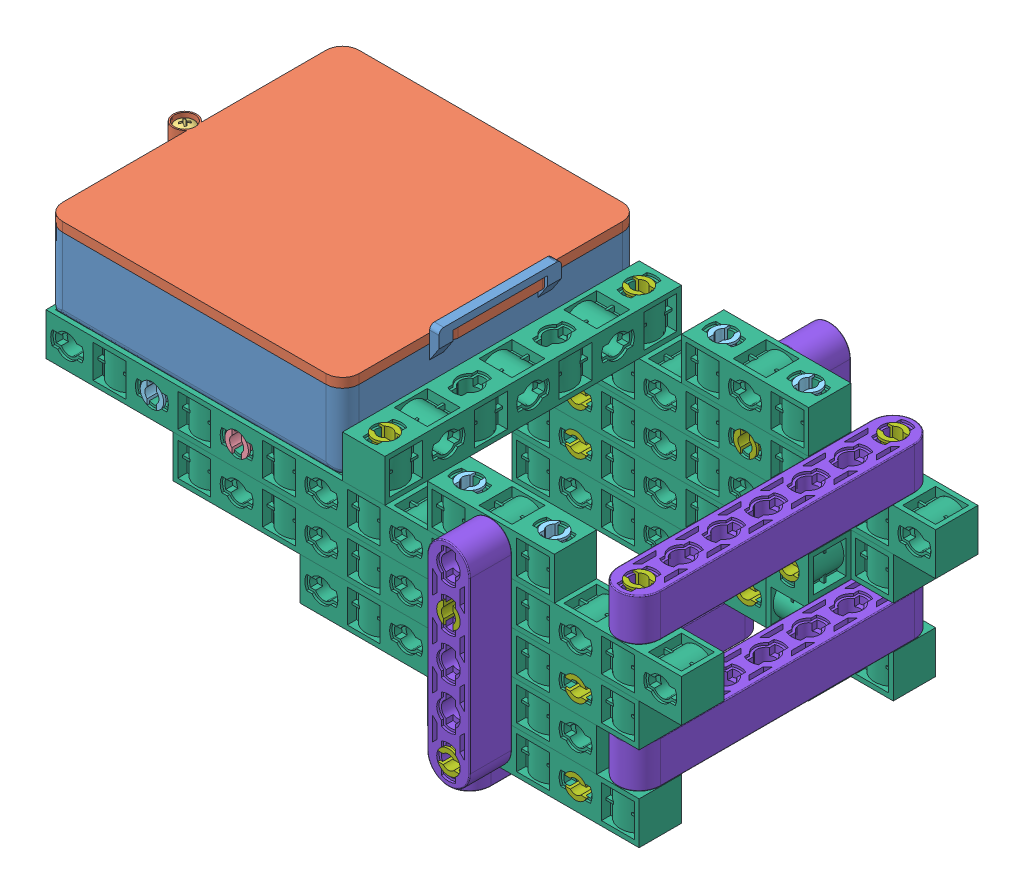
SolidWorks assembly Subconjunto Vigas traseiras, configuration Default. Lengths in mm.
Overall size (139.81 64.5 81).
57 component instances, 8 part files, 103 mates.
Components (placement in the parent):
- Subconjunto caixa pilhas-1: Subconjunto caixa pilhas [Default] at (12.3707 2.7009 -5.3452) size (69.81 28.5 63)
  - Caixa das pilhas-1: Caixa das pilhas [Default] at (12.7241 32.9375 62.5857) size (69.5 28.5 63)
  - Tampa compartimento das pilhas-1: Tampa compartimento das pilhas [Default] at (12.7241 42.9375 62.5857) x (0 0 1) z (1 0 0) size (63 4 69.5)
  - pan head cross recess screw_iso-4: pan head cross recess screw_iso [ISO 7045 - M2 x 6 - Z - 6N] at (-20.7759 42.7775 62.5857) x (0 -1 0) z (0.784317 0 0.62036) size (7.57 4 4)
- Pino Paralelo-2: Pino Paralelo [Default] at (34.0948 23.1383 79.7405) x (-1 0 0) z (0 -1 0) size (6 18 4.58)
- Pino Triplo Longo-1: Pino Triplo Longo [Default] at (16.0948 23.1383 75.2405) x (1 0 0) z (0 -1 0) size (6 27 4.58)
- Viga alternada-1: Viga alternada [Viga alternada de 15] at (61.0948 23.1383 84.2405) x (1 0 0) z (0 1 0) size (135 9 9)
- Pino Triplo Longo-2: Pino Triplo Longo [Default] at (97.0948 23.1383 84.2405) size (6 27 4.58)
- Pino Triplo Longo-3: Pino Triplo Longo [Default] at (79.0948 23.1383 84.2405) size (6 27 4.58)
- Viga alternada-2: Viga alternada [Viga alternada de 3] at (88.0948 32.1383 84.2405) size (27 9 9)
- Pino Perpendicular-1: Pino Perpendicular [Default] at (61.0948 27.6383 84.2405) x (0 0 -1) z (1 0 0) size (6 18 6)
- Viga alternada-3: Viga alternada [Viga alternada de 11] at (70.0948 14.1383 84.2405) size (99 9 9)
- Pino Paralelo-4: Pino Paralelo [Default] at (43.0948 18.6383 84.2405) size (6 18 4.58)
- Pino Paralelo-5: Pino Paralelo [Default] at (25.0948 18.6383 84.2405) size (6 18 4.58)
- Pino Paralelo-6: Pino Paralelo [Default] at (34.0948 23.1383 34.7405) x (-1 0 0) z (0 1 0) size (6 18 4.58)
- Pino Triplo Longo-4: Pino Triplo Longo [Default] at (16.0948 23.1383 39.2405) x (1 0 0) z (0 1 0) size (6 27 4.58)
- Viga alternada-4: Viga alternada [Viga alternada de 15] at (61.0948 23.1383 30.2405) x (1 0 0) z (0 -1 0) size (135 9 9)
- Pino Triplo Longo-5: Pino Triplo Longo [Default] at (97.0948 23.1383 30.2405) size (6 27 4.58)
- Pino Triplo Longo-6: Pino Triplo Longo [Default] at (79.0948 23.1383 30.2405) size (6 27 4.58)
- Viga alternada-5: Viga alternada [Viga alternada de 3] at (88.0948 32.1383 30.2405) size (27 9 9)
- Pino Perpendicular-2: Pino Perpendicular [Default] at (61.0948 27.6383 30.2405) x (0 0 1) z (-1 0 0) size (6 18 6)
- Viga alternada-6: Viga alternada [Viga alternada de 11] at (70.0948 14.1383 30.2405) size (99 9 9)
- Pino Paralelo-7: Pino Paralelo [Default] at (25.0948 18.6383 30.2405) size (6 18 4.58)
- Pino Perpendicular-3: Pino Perpendicular [Default] at (115.0948 27.6383 84.2405) x (0 0 1) z (-1 0 0) size (6 18 6)
- Pino Perpendicular-4: Pino Perpendicular [Default] at (115.0948 9.6383 84.2405) size (6 18 6)
- Pino Perpendicular-5: Pino Perpendicular [Default] at (115.0948 27.6383 30.2405) x (0 0 -1) z (1 0 0) size (6 18 6)
- Pino Perpendicular-6: Pino Perpendicular [Default] at (115.0948 9.6383 30.2405) size (6 18 6)
- Viga alternada-7: Viga alternada [Viga alternada de 7] at (61.0948 32.1383 57.2405) x (0 0 -1) z (1 0 0) size (63 9 9)
- Viga plana-1: Viga plana [Viga plana de 7] at (115.0948 32.1383 57.2405) x (0 0 1) z (-1 0 0) size (63 9 9)
- Viga plana-2: Viga plana [Viga plana de 7] at (115.0948 5.1383 57.2405) x (0 0 1) z (1 0 0) size (63 9 9)
- Pino Paralelo-8: Pino Paralelo [Default] at (61.0948 9.6383 84.2405) size (6 18 4.58)
- Viga alternada-8: Viga alternada [Viga alternada de 7] at (79.0948 5.1383 84.2405) x (1 0 0) z (0 -1 0) size (63 9 9)
- Pino Paralelo-9: Pino Paralelo [Default] at (97.0948 0.6383 84.2405) x (-1 0 0) z (0 0 -1) size (6 18 4.58)
- Pino Triplo Longo-7: Pino Triplo Longo [Default] at (79.0948 -3.8617 84.2405) x (-1 0 0) z (0 0 -1) size (6 27 4.58)
- Viga alternada-9: Viga alternada [Viga alternada de 5] at (97.0948 -3.8617 84.2405) size (45 9 9)
- Viga alternada-10: Viga alternada [Viga alternada de 9] at (70.0948 5.1383 30.2405) x (1 0 0) z (0 1 0) size (81 9 9)
- Viga alternada-11: Viga alternada [Viga alternada de 9] at (79.0948 -3.8617 30.2405) size (81 9 9)
- Pino Triplo Longo-8: Pino Triplo Longo [Default] at (61.0948 5.1383 30.2405) x (-1 0 0) z (0 0 1) size (6 27 4.58)
- Pino Triplo Longo-9: Pino Triplo Longo [Default] at (43.0948 5.1383 30.2405) x (1 0 0) z (0 0 -1) size (6 27 4.58)
- Pino Paralelo-10: Pino Paralelo [Default] at (97.0948 0.6383 30.2405) size (6 18 4.58)
- Pino Perpendicular-8: Pino Perpendicular [Default] at (79.0948 -8.3617 30.2405) size (6 18 6)
- Viga plana-3: Viga plana [Viga plana de 5] at (88.0948 14.1383 93.2405) x (0 -1 0) z (-1 0 0) size (45 9 9)
- Pino Perpendicular-9: Pino Perpendicular [Default] at (88.0948 -3.8617 88.7405) x (0 -1 0) z (-1 0 0) size (6 18 6)
- Viga plana-5: Viga plana [Viga plana de 7] at (79.0948 -12.8617 57.2405) x (0 0 1) z (-1 0 0) size (63 9 9)
- Viga alternada-12: Viga alternada [Viga alternada de 3 (Preta)] at (106.0948 5.1383 75.2405) x (0 -1 0) z (1 0 0) size (27 9 9)
- Pino Perpendicular-11: Pino Perpendicular [Default] at (106.0948 -3.8617 79.7405) x (0 -1 0) z (1 0 0) size (6 18 6)
- Pino Perpendicular-12: Pino Perpendicular [Default] at (106.0948 14.1383 79.7405) x (0 -1 0) z (1 0 0) size (6 18 6)
- Pino Perpendicular-13: Pino Perpendicular [Default] at (88.0948 -3.8617 25.7405) x (0 -1 0) z (1 0 0) size (6 18 6)
- Viga plana-6: Viga plana [Viga plana de 5] at (88.0948 14.1383 21.2405) x (0 -1 0) z (1 0 0) size (45 9 9)
- Pino Perpendicular-15: Pino Perpendicular [Default] at (106.0948 -3.8617 34.7405) x (0 -1 0) z (-1 0 0) size (6 18 6)
- Viga alternada-13: Viga alternada [Viga alternada de 3 (Preta)] at (106.0948 5.1383 39.2405) x (0 -1 0) z (-1 0 0) size (27 9 9)
- Pino Perpendicular-16: Pino Perpendicular [Default] at (106.0948 14.1383 34.7405) x (0 -1 0) z (-1 0 0) size (6 18 6)
- Viga plana-7: Viga plana [Viga plana de 3] at (52.0948 5.1383 21.2405) x (0 1 0) z (-1 0 0) size (27 9 9)
- Pino Perpendicular-17: Pino Perpendicular [Default] at (52.0948 14.1383 25.7405) x (0 1 0) z (-1 0 0) size (6 18 6)
- Pino Perpendicular-18: Pino Perpendicular [Default] at (52.0948 5.1383 25.7405) x (0 1 0) z (-1 0 0) size (6 18 6)
- Pino Perpendicular-19: Pino Perpendicular [Default] at (88.0948 23.1383 88.7405) x (1 0 0) z (0 1 0) size (6 18 6)
- Pino Perpendicular-20: Pino Perpendicular [Default] at (88.0948 23.1383 25.7405) x (1 0 0) z (0 -1 0) size (6 18 6)
Mates (geometry in assembly coordinates):
- Coincident11: coincident aligned: plane of Subconjunto caixa pilhas-1/Caixa das pilhas-1 through (2.5948 18.6383 70.7405) normal (0 0 -1); plane of Pino Paralelo-2 through (34.0948 23.1383 70.7405) normal (0 0 -1)
- Concentric11: concentric aligned: cylinder of Subconjunto caixa pilhas-1/Caixa das pilhas-1 through (34.0948 23.1383 88.7405) axis (0 0 -1) radius 2; cylinder of Pino Paralelo-2 through (34.0948 23.1383 70.7405) axis (0 0 -1) radius 2
- Parallel11: parallel anti-aligned: plane of Subconjunto caixa pilhas-1/Caixa das pilhas-1 through (25.0948 24.1383 77.7405) normal (0 -1 0); plane of Pino Paralelo-2 through (34.0948 24.1383 79.7405) normal (0 1 0)
- Concentric2: concentric anti-aligned: cylinder of Subconjunto caixa pilhas-1/Caixa das pilhas-1 through (16.0948 23.1383 88.7405) axis (0 0 -1) radius 2; cylinder of Pino Triplo Longo-1 through (16.0948 23.1383 88.7405) axis (0 0 1) radius 2
- Coincident3: coincident anti-aligned: plane of Subconjunto caixa pilhas-1/Caixa das pilhas-1 through (25.0948 24.1383 72.7405) normal (0 -1 0); plane of Pino Triplo Longo-1 through (16.0948 24.1383 75.2405) normal (0 1 0)
- Coincident4: coincident aligned: plane of Pino Paralelo-2 through (34.0948 23.1383 88.7405) normal (0 0 1); plane of Pino Triplo Longo-1 through (16.0948 23.1383 88.7405) normal (0 0 1)
- Concentric3: concentric anti-aligned: cylinder of Pino Triplo Longo-1 through (16.0948 23.1383 88.7405) axis (0 0 1) radius 2; cylinder of Viga alternada-1 through (16.0948 23.1383 88.7405) axis (0 0 -1) radius 2
- Concentric4: concentric aligned: cylinder of Pino Paralelo-2 through (34.0948 23.1383 70.7405) axis (0 0 -1) radius 2; cylinder of Viga alternada-1 through (34.0948 23.1383 88.7405) axis (0 0 -1) radius 2
- Coincident5: coincident aligned: plane of Pino Triplo Longo-1 through (16.0948 23.1383 88.7405) normal (0 0 1); plane of Viga alternada-1 through (61.0948 23.1383 88.7405) normal (0 0 1)
- Coincident6: coincident aligned: plane of Pino Triplo Longo-2 through (97.0948 36.6383 84.2405) normal (0 1 0); plane of Pino Triplo Longo-3 through (79.0948 36.6383 84.2405) normal (0 1 0)
- Concentric7: concentric aligned: cylinder of Pino Triplo Longo-2 through (97.0948 36.6383 84.2405) axis (0 1 0) radius 2; cylinder of Viga alternada-2 through (97.0948 27.6383 84.2405) axis (0 1 0) radius 2
- Concentric8: concentric aligned: cylinder of Pino Triplo Longo-3 through (79.0948 36.6383 84.2405) axis (0 1 0) radius 2; cylinder of Viga alternada-2 through (79.0948 28.6383 84.2405) axis (0 1 0) radius 4
- Coincident7: coincident anti-aligned: plane of Pino Triplo Longo-3 through (79.0948 23.1383 85.2405) normal (0 0 1); plane of Viga alternada-2 through (88.0948 34.6383 85.2405) normal (0 0 -1)
- Coincident8: coincident anti-aligned: plane of Pino Triplo Longo-2 through (97.0948 23.1383 83.2405) normal (0 0 -1); plane of Viga alternada-2 through (106.0948 34.6383 83.2405) normal (0 0 1)
- Coincident9: coincident aligned: plane of Pino Triplo Longo-2 through (97.0948 36.6383 84.2405) normal (0 1 0); plane of Viga alternada-2 through (88.0948 36.6383 84.2405) normal (0 1 0)
- Coincident10: coincident anti-aligned: plane of Viga alternada-1 through (-6.4052 27.6383 79.7405) normal (0 1 0); plane of Viga alternada-2 through (88.0948 27.6383 84.2405) normal (0 -1 0)
- Concentric9: concentric aligned: cylinder of Viga alternada-1 through (61.0948 18.6383 84.2405) axis (0 1 0) radius 2; cylinder of Pino Perpendicular-1 through (61.0948 36.6383 84.2405) axis (0 1 0) radius 2
- Concentric10: concentric aligned: cylinder of Viga alternada-1 through (97.0948 18.6383 84.2405) axis (0 1 0) radius 2; cylinder of Pino Triplo Longo-2 through (97.0948 36.6383 84.2405) axis (0 1 0) radius 2
- Concentric11: concentric aligned: cylinder of Viga alternada-1 through (79.0948 18.6383 84.2405) axis (0 1 0) radius 2; cylinder of Pino Triplo Longo-3 through (79.0948 36.6383 84.2405) axis (0 1 0) radius 2
- Concentric12: concentric aligned: cylinder of Viga alternada-3 through (25.0948 9.6383 84.2405) axis (0 1 0) radius 2; cylinder of Pino Paralelo-5 through (25.0948 27.6383 84.2405) axis (0 1 0) radius 2
- Concentric13: concentric aligned: cylinder of Viga alternada-3 through (43.0948 9.6383 84.2405) axis (0 1 0) radius 2; cylinder of Pino Paralelo-4 through (43.0948 27.6383 84.2405) axis (0 1 0) radius 2
- Parallel2: parallel aligned: plane of Pino Paralelo-4 through (43.0948 18.6383 85.2405) normal (0 0 1); plane of Pino Paralelo-5 through (25.0948 18.6383 85.2405) normal (0 0 1)
- Coincident14: coincident anti-aligned: plane of Viga alternada-3 through (88.0948 11.6383 83.2405) normal (0 0 1); plane of Pino Paralelo-4 through (43.0948 18.6383 83.2405) normal (0 0 -1)
- Coincident15: coincident aligned: plane of Pino Paralelo-4 through (43.0948 9.6383 84.2405) normal (0 -1 0); plane of Pino Paralelo-5 through (25.0948 9.6383 84.2405) normal (0 -1 0)
- Coincident16: coincident aligned: plane of Viga alternada-3 through (70.0948 9.6383 84.2405) normal (0 -1 0); plane of Pino Paralelo-5 through (25.0948 9.6383 84.2405) normal (0 -1 0)
- Concentric14: concentric aligned: cylinder of Pino Triplo Longo-2 through (97.0948 5.3957 84.2405) axis (0 1 0) radius 1.5; cylinder of Viga alternada-3 through (97.0948 9.6383 84.2405) axis (0 1 0) radius 2
- Concentric15: concentric aligned: cylinder of Pino Triplo Longo-3 through (79.0948 36.6383 84.2405) axis (0 1 0) radius 2; cylinder of Viga alternada-3 through (79.0948 9.6383 84.2405) axis (0 1 0) radius 2
- Coincident17: coincident anti-aligned: plane of Viga alternada-1 through (-6.4052 18.6383 79.7405) normal (0 -1 0); plane of Viga alternada-3 through (70.0948 18.6383 84.2405) normal (0 1 0)
- Coincident18: coincident aligned: plane of Viga alternada-1 through (-6.4052 18.6383 79.7405) normal (0 -1 0); plane of Pino Perpendicular-1 through (61.0948 18.6383 84.2405) normal (0 -1 0)
- Concentric16: concentric aligned: cylinder of Viga alternada-1 through (115.0948 18.6383 84.2405) axis (0 1 0) radius 2; cylinder of Pino Perpendicular-3 through (115.0948 36.6383 84.2405) axis (0 1 0) radius 2
- Parallel12: parallel anti-aligned: plane of Viga alternada-1 through (169.0948 25.6383 85.2405) normal (0 0 -1); plane of Pino Perpendicular-3 through (115.0948 27.6383 85.2405) normal (0 0 1)
- Coincident22: coincident aligned: plane of Viga alternada-1 through (-6.4052 18.6383 79.7405) normal (0 -1 0); plane of Pino Perpendicular-3 through (115.0948 18.6383 84.2405) normal (0 -1 0)
- Concentric17: concentric aligned: cylinder of Viga alternada-3 through (115.0948 9.6383 84.2405) axis (0 1 0) radius 2; cylinder of Pino Perpendicular-4 through (115.0948 18.6383 84.2405) axis (0 1 0) radius 2
- Coincident23: coincident anti-aligned: plane of Viga alternada-3 through (160.0948 11.6383 85.2405) normal (0 0 -1); plane of Pino Perpendicular-4 through (115.0948 9.6383 85.2405) normal (0 0 1)
- Coincident24: coincident anti-aligned: plane of Viga alternada-1 through (-6.4052 18.6383 79.7405) normal (0 -1 0); plane of Pino Perpendicular-4 through (115.0948 18.6383 84.2405) normal (0 1 0)
- Concentric20: concentric aligned: cylinder of Pino Perpendicular-1 through (61.0948 36.6383 84.2405) axis (0 1 0) radius 2; cylinder of Viga alternada-7 through (61.0948 27.6383 84.2405) axis (0 1 0) radius 2
- Concentric21: concentric aligned: cylinder of Pino Perpendicular-2 through (61.0948 36.6383 30.2405) axis (0 1 0) radius 2; cylinder of Viga alternada-7 through (61.0948 27.6383 30.2405) axis (0 1 0) radius 2
- Coincident25: coincident anti-aligned: plane of Viga alternada-1 through (115.0948 25.6383 83.2405) normal (0 0 1); plane of Pino Perpendicular-1 through (61.0948 27.6383 83.2405) normal (0 0 -1)
- Coincident26: coincident anti-aligned: plane of Viga alternada-1 through (-6.4052 27.6383 79.7405) normal (0 1 0); plane of Viga alternada-7 through (61.0948 27.6383 57.2405) normal (0 -1 0)
- Concentric22: concentric aligned: cylinder of Pino Perpendicular-3 through (115.0948 36.6383 84.2405) axis (0 1 0) radius 2; cylinder of Viga plana-1 through (115.0948 27.6383 84.2405) axis (0 1 0) radius 2
- Concentric23: concentric aligned: cylinder of Pino Perpendicular-5 through (115.0948 36.6383 30.2405) axis (0 1 0) radius 2; cylinder of Viga plana-1 through (115.0948 27.6383 30.2405) axis (0 1 0) radius 2
- Coincident27: coincident anti-aligned: plane of Viga alternada-1 through (-6.4052 27.6383 79.7405) normal (0 1 0); plane of Viga plana-1 through (115.0948 27.6383 30.2405) normal (0 -1 0)
- Concentric24: concentric aligned: cylinder of Viga alternada-3 through (61.0948 9.6383 84.2405) axis (0 1 0) radius 2; cylinder of Pino Paralelo-8 through (61.0948 18.6383 84.2405) axis (0 1 0) radius 2
- Coincident28: coincident anti-aligned: plane of Viga alternada-3 through (106.0948 11.6383 85.2405) normal (0 0 -1); plane of Pino Paralelo-8 through (61.0948 9.6383 85.2405) normal (0 0 1)
- Coincident30: coincident aligned: plane of Viga alternada-3 through (70.0948 18.6383 84.2405) normal (0 1 0); plane of Pino Paralelo-8 through (61.0948 18.6383 84.2405) normal (0 1 0)
- Concentric25: concentric anti-aligned: cylinder of Pino Paralelo-8 through (61.0948 18.6383 84.2405) axis (0 1 0) radius 2; cylinder of Viga alternada-8 through (61.0948 9.6383 84.2405) axis (0 -1 0) radius 2
- Coincident31: coincident anti-aligned: plane of Pino Paralelo-8 through (61.0948 9.6383 85.2405) normal (0 0 1); plane of Viga alternada-8 through (79.0948 2.6383 85.2405) normal (0 0 -1)
- Coincident32: coincident aligned: plane of Pino Paralelo-8 through (61.0948 0.6383 84.2405) normal (0 -1 0); plane of Viga alternada-8 through (47.5948 0.6383 88.7405) normal (0 -1 0)
- Concentric26: concentric anti-aligned: cylinder of Viga alternada-8 through (79.0948 9.6383 84.2405) axis (0 -1 0) radius 2; cylinder of Pino Triplo Longo-7 through (79.0948 9.6383 84.2405) axis (0 1 0) radius 2
- Parallel13: parallel aligned: plane of Pino Paralelo-9 through (97.0948 0.6383 83.2405) normal (0 0 -1); plane of Pino Triplo Longo-7 through (79.0948 -3.8617 83.2405) normal (0 0 -1)
- Concentric27: concentric anti-aligned: cylinder of Viga alternada-8 through (97.0948 9.6383 84.2405) axis (0 -1 0) radius 2; cylinder of Pino Paralelo-9 through (97.0948 9.6383 84.2405) axis (0 1 0) radius 2
- Coincident33: coincident anti-aligned: plane of Viga alternada-8 through (97.0948 2.6383 83.2405) normal (0 0 1); plane of Pino Triplo Longo-7 through (79.0948 -3.8617 83.2405) normal (0 0 -1)
- Parallel14: parallel aligned: plane of Pino Paralelo-9 through (97.0948 9.6383 84.2405) normal (0 1 0); plane of Pino Triplo Longo-7 through (79.0948 9.6383 84.2405) normal (0 1 0)
- Coincident34: coincident aligned: plane of Pino Paralelo-9 through (97.0948 9.6383 84.2405) normal (0 1 0); plane of Pino Triplo Longo-7 through (79.0948 9.6383 84.2405) normal (0 1 0)
- Coincident35: coincident aligned: plane of Viga alternada-8 through (47.5948 9.6383 88.7405) normal (0 1 0); plane of Pino Triplo Longo-7 through (79.0948 9.6383 84.2405) normal (0 1 0)
- Concentric28: concentric aligned: cylinder of Pino Paralelo-9 through (97.0948 9.6383 84.2405) axis (0 1 0) radius 2; cylinder of Viga alternada-9 through (97.0948 -8.3617 84.2405) axis (0 1 0) radius 2
- Concentric29: concentric aligned: cylinder of Pino Triplo Longo-7 through (79.0948 9.6383 84.2405) axis (0 1 0) radius 2; cylinder of Viga alternada-9 through (79.0948 -8.3617 84.2405) axis (0 1 0) radius 2
- Coincident36: coincident anti-aligned: plane of Viga alternada-8 through (47.5948 0.6383 88.7405) normal (0 -1 0); plane of Viga alternada-9 through (97.0948 0.6383 84.2405) normal (0 1 0)
- Concentric31: concentric anti-aligned: cylinder of Viga alternada-6 through (43.0948 9.6383 30.2405) axis (0 1 0) radius 2; cylinder of Pino Triplo Longo-9 through (43.0948 -8.3617 30.2405) axis (0 -1 0) radius 2
- Concentric32: concentric anti-aligned: cylinder of Viga alternada-6 through (61.0948 9.6383 30.2405) axis (0 1 0) radius 2; cylinder of Pino Triplo Longo-8 through (61.0948 -8.3617 30.2405) axis (0 -1 0) radius 2
- Coincident37: coincident aligned: plane of Pino Triplo Longo-8 through (61.0948 -8.3617 30.2405) normal (0 -1 0); plane of Pino Triplo Longo-9 through (43.0948 -8.3617 30.2405) normal (0 -1 0)
- Coincident38: coincident aligned: plane of Pino Triplo Longo-8 through (61.0948 5.1383 29.2405) normal (0 0 -1); plane of Pino Triplo Longo-9 through (43.0948 5.1383 29.2405) normal (0 0 -1)
- Concentric33: concentric anti-aligned: cylinder of Viga alternada-10 through (43.0948 0.6383 30.2405) axis (0 1 0) radius 2; cylinder of Pino Triplo Longo-9 through (43.0948 -8.3617 30.2405) axis (0 -1 0) radius 2
- Concentric34: concentric anti-aligned: cylinder of Viga alternada-10 through (61.0948 0.6383 30.2405) axis (0 1 0) radius 2; cylinder of Pino Triplo Longo-8 through (61.0948 -8.3617 30.2405) axis (0 -1 0) radius 2
- Coincident41: coincident aligned: plane of Viga alternada-6 through (70.0948 18.6383 30.2405) normal (0 1 0); plane of Pino Triplo Longo-8 through (61.0948 18.6383 30.2405) normal (0 1 0)
- Coincident42: coincident anti-aligned: plane of Viga alternada-6 through (70.0948 9.6383 30.2405) normal (0 -1 0); plane of Viga alternada-10 through (29.5948 9.6383 25.7405) normal (0 1 0)
- Concentric35: concentric aligned: cylinder of Viga alternada-10 through (97.0948 0.6383 30.2405) axis (0 1 0) radius 2; cylinder of Pino Paralelo-10 through (97.0948 9.6383 30.2405) axis (0 1 0) radius 2
- Coincident43: coincident aligned: plane of Pino Triplo Longo-8 through (61.0948 5.1383 29.2405) normal (0 0 -1); plane of Pino Paralelo-10 through (97.0948 0.6383 29.2405) normal (0 0 -1)
- Coincident44: coincident aligned: plane of Viga alternada-10 through (29.5948 9.6383 25.7405) normal (0 1 0); plane of Pino Paralelo-10 through (97.0948 9.6383 30.2405) normal (0 1 0)
- Concentric36: concentric anti-aligned: cylinder of Viga alternada-11 through (43.0948 -8.3617 30.2405) axis (0 1 0) radius 2; cylinder of Pino Triplo Longo-9 through (43.0948 -8.3617 30.2405) axis (0 -1 0) radius 2
- Concentric37: concentric aligned: cylinder of Viga alternada-11 through (97.0948 -8.3617 30.2405) axis (0 1 0) radius 2; cylinder of Pino Paralelo-10 through (97.0948 9.6383 30.2405) axis (0 1 0) radius 2
- Coincident45: coincident anti-aligned: plane of Viga alternada-10 through (29.5948 0.6383 25.7405) normal (0 -1 0); plane of Viga alternada-11 through (79.0948 0.6383 30.2405) normal (0 1 0)
- Concentric38: concentric aligned: cylinder of Viga alternada-11 through (79.0948 -8.3617 30.2405) axis (0 1 0) radius 2; cylinder of Pino Perpendicular-8 through (79.0948 0.6383 30.2405) axis (0 1 0) radius 2
- Coincident46: coincident anti-aligned: plane of Viga alternada-11 through (115.0948 -6.3617 29.2405) normal (0 0 1); plane of Pino Perpendicular-8 through (79.0948 -8.3617 29.2405) normal (0 0 -1)
- Coincident47: coincident aligned: plane of Viga alternada-11 through (79.0948 0.6383 30.2405) normal (0 1 0); plane of Pino Perpendicular-8 through (79.0948 0.6383 30.2405) normal (0 1 0)
- Concentric39: concentric aligned: cylinder of Viga plana-3 through (88.0948 -3.8617 88.7405) axis (0 0 1) radius 2; cylinder of Pino Perpendicular-9 through (88.0948 -3.8617 97.7405) axis (0 0 1) radius 2
- Coincident51: coincident aligned: plane of Viga plana-3 through (88.0948 32.1383 97.7405) normal (0 0 1); plane of Pino Perpendicular-9 through (88.0948 -3.8617 97.7405) normal (0 0 1)
- Concentric44: concentric aligned: cylinder of Pino Triplo Longo-7 through (79.0948 9.6383 84.2405) axis (0 1 0) radius 2; cylinder of Viga plana-5 through (79.0948 -17.3617 84.2405) axis (0 1 0) radius 2
- Concentric45: concentric aligned: cylinder of Pino Perpendicular-8 through (79.0948 0.6383 30.2405) axis (0 1 0) radius 2; cylinder of Viga plana-5 through (79.0948 -17.3617 30.2405) axis (0 1 0) radius 2
- Coincident52: coincident anti-aligned: plane of Viga alternada-9 through (97.0948 -8.3617 84.2405) normal (0 -1 0); plane of Viga plana-5 through (79.0948 -8.3617 30.2405) normal (0 1 0)
- Concentric46: concentric aligned: cylinder of Viga alternada-9 through (88.0948 -3.8617 79.7405) axis (0 0 1) radius 2; cylinder of Pino Perpendicular-9 through (88.0948 -3.8617 97.7405) axis (0 0 1) radius 2
- Coincident53: coincident aligned: plane of Viga alternada-9 through (74.5948 0.6383 79.7405) normal (0 0 -1); plane of Pino Perpendicular-9 through (88.0948 -3.8617 79.7405) normal (0 0 -1)
- Concentric48: concentric aligned: cylinder of Viga alternada-12 through (106.0948 -3.8617 79.7405) axis (0 0 -1) radius 2; cylinder of Pino Perpendicular-11 through (106.0948 -3.8617 70.7405) axis (0 0 -1) radius 2
- Concentric49: concentric aligned: cylinder of Viga alternada-12 through (106.0948 14.1383 79.7405) axis (0 0 -1) radius 2; cylinder of Pino Perpendicular-12 through (106.0948 14.1383 70.7405) axis (0 0 -1) radius 2
- Coincident54: coincident aligned: plane of Pino Perpendicular-11 through (107.0948 -3.8617 79.7405) normal (1 0 0); plane of Pino Perpendicular-12 through (107.0948 14.1383 79.7405) normal (1 0 0)
- Coincident55: coincident anti-aligned: plane of Viga alternada-12 through (105.0948 5.1383 77.7405) normal (1 0 0); plane of Pino Perpendicular-12 through (105.0948 14.1383 79.7405) normal (-1 0 0)
- Coincident56: coincident aligned: plane of Viga alternada-12 through (106.0948 5.1383 70.7405) normal (0 0 -1); plane of Pino Perpendicular-11 through (106.0948 -3.8617 70.7405) normal (0 0 -1)
- Coincident57: coincident aligned: plane of Pino Perpendicular-11 through (106.0948 -3.8617 70.7405) normal (0 0 -1); plane of Pino Perpendicular-12 through (106.0948 14.1383 70.7405) normal (0 0 -1)
- Concentric50: concentric anti-aligned: cylinder of Viga alternada-9 through (106.0948 -3.8617 79.7405) axis (0 0 1) radius 2; cylinder of Pino Perpendicular-11 through (106.0948 -3.8617 70.7405) axis (0 0 -1) radius 2
- Concentric51: concentric anti-aligned: cylinder of Viga alternada-3 through (106.0948 14.1383 79.7405) axis (0 0 1) radius 2; cylinder of Pino Perpendicular-12 through (106.0948 14.1383 70.7405) axis (0 0 -1) radius 2
- Coincident58: coincident anti-aligned: plane of Viga alternada-9 through (74.5948 0.6383 79.7405) normal (0 0 -1); plane of Viga alternada-12 through (106.0948 5.1383 79.7405) normal (0 0 1)
- Concentric52: concentric aligned: cylinder of Viga plana-7 through (52.0948 5.1383 25.7405) axis (0 0 -1) radius 2; cylinder of Pino Perpendicular-18 through (52.0948 5.1383 16.7405) axis (0 0 -1) radius 2
- Concentric53: concentric aligned: cylinder of Viga plana-7 through (52.0948 14.1383 25.7405) axis (0 0 -1) radius 2; cylinder of Pino Perpendicular-17 through (52.0948 14.1383 16.7405) axis (0 0 -1) radius 2
- Coincident59: coincident anti-aligned: plane of Viga plana-7 through (51.0948 14.1383 23.7405) normal (1 0 0); plane of Pino Perpendicular-18 through (51.0948 5.1383 25.7405) normal (-1 0 0)
- Coincident60: coincident aligned: plane of Pino Perpendicular-17 through (53.0948 14.1383 25.7405) normal (1 0 0); plane of Pino Perpendicular-18 through (53.0948 5.1383 25.7405) normal (1 0 0)
- Coincident61: coincident aligned: plane of Pino Perpendicular-17 through (52.0948 14.1383 34.7405) normal (0 0 1); plane of Pino Perpendicular-18 through (52.0948 5.1383 34.7405) normal (0 0 1)
- Coincident62: coincident aligned: plane of Viga plana-7 through (52.0948 -3.8617 16.7405) normal (0 0 -1); plane of Pino Perpendicular-18 through (52.0948 5.1383 16.7405) normal (0 0 -1)
- Concentric54: concentric anti-aligned: cylinder of Viga alternada-11 through (52.0948 -3.8617 25.7405) axis (0 0 1) radius 2; cylinder of Viga plana-7 through (52.0948 -3.8617 25.7405) axis (0 0 -1) radius 2
- Concentric55: concentric anti-aligned: cylinder of Viga alternada-6 through (52.0948 14.1383 25.7405) axis (0 0 1) radius 2; cylinder of Pino Perpendicular-17 through (52.0948 14.1383 38.9831) axis (0 0 -1) radius 1.5
- Coincident63: coincident aligned: plane of Viga alternada-10 through (70.0948 5.1383 34.7405) normal (0 0 1); plane of Pino Perpendicular-18 through (52.0948 5.1383 34.7405) normal (0 0 1)
- Concentric56: concentric anti-aligned: cylinder of Viga plana-3 through (88.0948 23.1383 88.7405) axis (0 0 1) radius 2; cylinder of Pino Perpendicular-19 through (88.0948 23.1383 79.7405) axis (0 0 -1) radius 2
- Coincident64: coincident anti-aligned: plane of Viga plana-3 through (87.0948 5.1383 95.7405) normal (1 0 0); plane of Pino Perpendicular-19 through (87.0948 23.1383 88.7405) normal (-1 0 0)
- Coincident65: coincident aligned: plane of Viga plana-3 through (88.0948 32.1383 97.7405) normal (0 0 1); plane of Pino Perpendicular-19 through (88.0948 23.1383 97.7405) normal (0 0 1)
